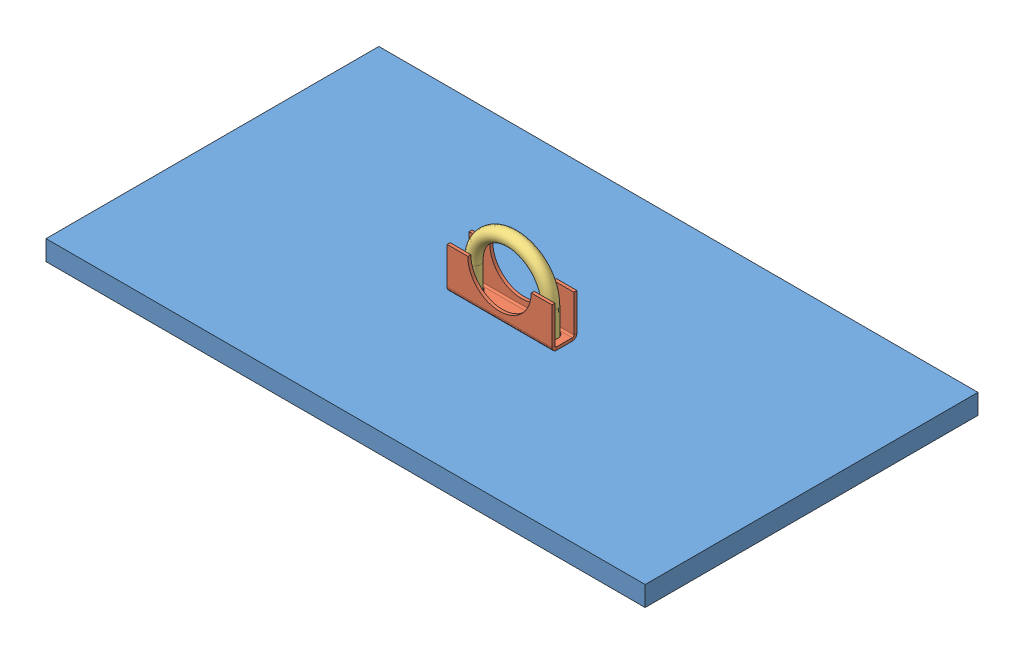
SolidWorks assembly Montagem_Placa_de_Calibracao, configuration Valor predeterminado. Lengths in mm.
Overall size (320 91.03 170).
7 component instances, 4 part files, 24 mates.
Components (placement in the parent):
- Placa-1: Placa [Valor predeterminado] at (18.0321 -23.8402 360) size (320 12 170)
- Encaixe_Placa_de_Calibracao-1: Encaixe_Placa_de_Calibracao [Default] at (158.0321 -23.8402 295) x (0 0 -1) z (-1 0 0) size (40 35 40)
- Encaixe_Placa_de_Calibracao-2: Encaixe_Placa_de_Calibracao [Default] at (158.0321 -23.8402 425) x (0 0 -1) z (-1 0 0) size (40 35 40)
- Encaixe_Placa_de_Calibracao-3: Encaixe_Placa_de_Calibracao [Default] at (-121.9679 -23.8402 295) x (0 0 -1) z (-1 0 0) size (40 35 40)
- Encaixe_Placa_de_Calibracao-4: Encaixe_Placa_de_Calibracao [Default] at (-121.9679 -23.8402 425) x (0 0 -1) z (-1 0 0) size (40 35 40)
- Abracadeira_Grampo_U_Placa_de_Calibracao_Base-1: Abracadeira_Grampo_U_Placa_de_Calibracao_Base [Valor predeterminado] at (-13.4679 13.1598 352.5) x (0 0 1) z (1 0 0) size (15 25 63)
- Abracadeira_Grampo_U_Placa_de_Calibracao_Argola-1: Abracadeira_Grampo_U_Placa_de_Calibracao_Argola [Valor predeterminado] at (18.0321 5.1388 360) x (0 -1 0) z (0 0 1) size (77.62 54.23 8.06)
Mates (geometry in assembly coordinates):
- Coincidente3: coincident anti-aligned: plane of Placa-1 through (18.0321 -23.8402 360) normal (0 -1 0); plane of ? through (-141.9679 -23.8402 280) normal (0 1 0)
- Coincidente4: coincident: plane of Placa-1 through (18.0321 -23.8402 360) normal (0 -1 0); plane of ? through (-141.9679 -23.8402 425.6098) normal (0 1 0)
- Coincidente5: coincident anti-aligned: plane of Placa-1 through (18.0321 -23.8402 360) normal (0 -1 0); plane of Encaixe_Placa_de_Calibracao-1 through (158.0321 -23.8402 295) normal (0 1 0)
- Coincidente6: coincident anti-aligned: plane of Placa-1 through (18.0321 -23.8402 360) normal (0 -1 0); plane of Encaixe_Placa_de_Calibracao-2 through (158.0321 -23.8402 425) normal (0 1 0)
- Coincidente7: coincident aligned: plane of Placa-1 through (-161.9679 -11.8402 460) normal (-1 0 0); plane of ? through (-161.9679 -33.8402 280) normal (-1 0 0)
- Coincidente8: coincident: plane of Placa-1 through (-161.9679 -11.8402 460) normal (-1 0 0); plane of ? through (-161.9679 -33.8402 425.6098) normal (-1 0 0)
- Coincidente9: coincident aligned: plane of Placa-1 through (178.0321 -11.8402 445) normal (1 0 0); plane of Encaixe_Placa_de_Calibracao-2 through (178.0321 -28.8402 425) normal (1 0 0)
- Coincidente10: coincident aligned: plane of Placa-1 through (178.0321 -11.8402 445) normal (1 0 0); plane of Encaixe_Placa_de_Calibracao-1 through (178.0321 -28.8402 295) normal (1 0 0)
- Coincidente13: coincident aligned: plane of Placa-1 through (-161.9679 -11.8402 260) normal (0 0 -1); plane of ? through (-141.9679 -33.8402 260) normal (0 0 -1)
- Coincidente14: coincident aligned: plane of Placa-1 through (-161.9679 -11.8402 460) normal (0 0 1); plane of ? through (-141.9679 -33.8402 460) normal (0 0 1)
- Coincidente15: coincident aligned: plane of Placa-1 through (-141.9679 -11.8402 445) normal (0 0 1); plane of Encaixe_Placa_de_Calibracao-2 through (158.0321 -28.8402 445) normal (0 0 1)
- Coincidente16: coincident aligned: plane of Placa-1 through (-141.9679 -11.8402 275) normal (0 0 -1); plane of Encaixe_Placa_de_Calibracao-1 through (158.0321 -28.8402 275) normal (0 0 -1)
- Coincidente17: coincident aligned: plane of Placa-1 through (-141.9679 -11.8402 445) normal (0 0 1); plane of Encaixe_Placa_de_Calibracao-4 through (-121.9679 -28.8402 445) normal (0 0 1)
- Coincidente18: coincident aligned: plane of Placa-1 through (-141.9679 -11.8402 445) normal (-1 0 0); plane of Encaixe_Placa_de_Calibracao-4 through (-141.9679 -28.8402 425) normal (-1 0 0)
- Coincidente19: coincident aligned: plane of Placa-1 through (-141.9679 -11.8402 445) normal (-1 0 0); plane of Encaixe_Placa_de_Calibracao-3 through (-141.9679 -28.8402 295) normal (-1 0 0)
- Coincidente20: coincident aligned: plane of Placa-1 through (-141.9679 -11.8402 275) normal (0 0 -1); plane of Encaixe_Placa_de_Calibracao-3 through (-121.9679 -28.8402 275) normal (0 0 -1)
- Coincidente21: coincident anti-aligned: plane of Placa-1 through (18.0321 -23.8402 360) normal (0 -1 0); plane of Encaixe_Placa_de_Calibracao-3 through (-121.9679 -23.8402 295) normal (0 1 0)
- Coincidente22: coincident anti-aligned: plane of Placa-1 through (18.0321 -23.8402 360) normal (0 -1 0); plane of Encaixe_Placa_de_Calibracao-4 through (-121.9679 -23.8402 425) normal (0 1 0)
- Coincidente23: coincident anti-aligned: plane of Placa-1 through (18.0321 -11.8402 360) normal (0 1 0); plane of ? through (140.0749 -11.8402 62.3972) normal (0 -1 0)
- Coincidente24: coincident anti-aligned: plane of Placa-1 through (18.0321 -11.8402 360) normal (0 1 0); plane of Abracadeira_Grampo_U_Placa_de_Calibracao_Base-1 through (49.5321 -11.8402 352.5) normal (0 -1 0)
- Concêntrico1: concentric aligned: cylinder of Abracadeira_Grampo_U_Placa_de_Calibracao_Base-1 through (-5.0179 13.1608 360) axis (0 -1 0) radius 4.5; cylinder of Abracadeira_Grampo_U_Placa_de_Calibracao_Argola-1 through (-5.0179 5.1388 360) axis (0 -1 0) radius 4
- Concêntrico3: concentric anti-aligned: cylinder of Abracadeira_Grampo_U_Placa_de_Calibracao_Base-1 through (41.0821 13.1608 360) axis (0 -1 0) radius 4.5; cylinder of Abracadeira_Grampo_U_Placa_de_Calibracao_Argola-1 through (41.0821 -44.8612 360) axis (0 1 0) radius 4
- Coincidente29: coincident aligned: cylinder of Placa-1 through (-5.0179 -23.8402 360) axis (0 1 0) radius 4.5; circle of Abracadeira_Grampo_U_Placa_de_Calibracao_Base-1
- Coincidente33: coincident anti-aligned: cylinder of Placa-1 through (41.0821 -23.8402 360) axis (0 1 0) radius 4.5; circle of Abracadeira_Grampo_U_Placa_de_Calibracao_Base-1
